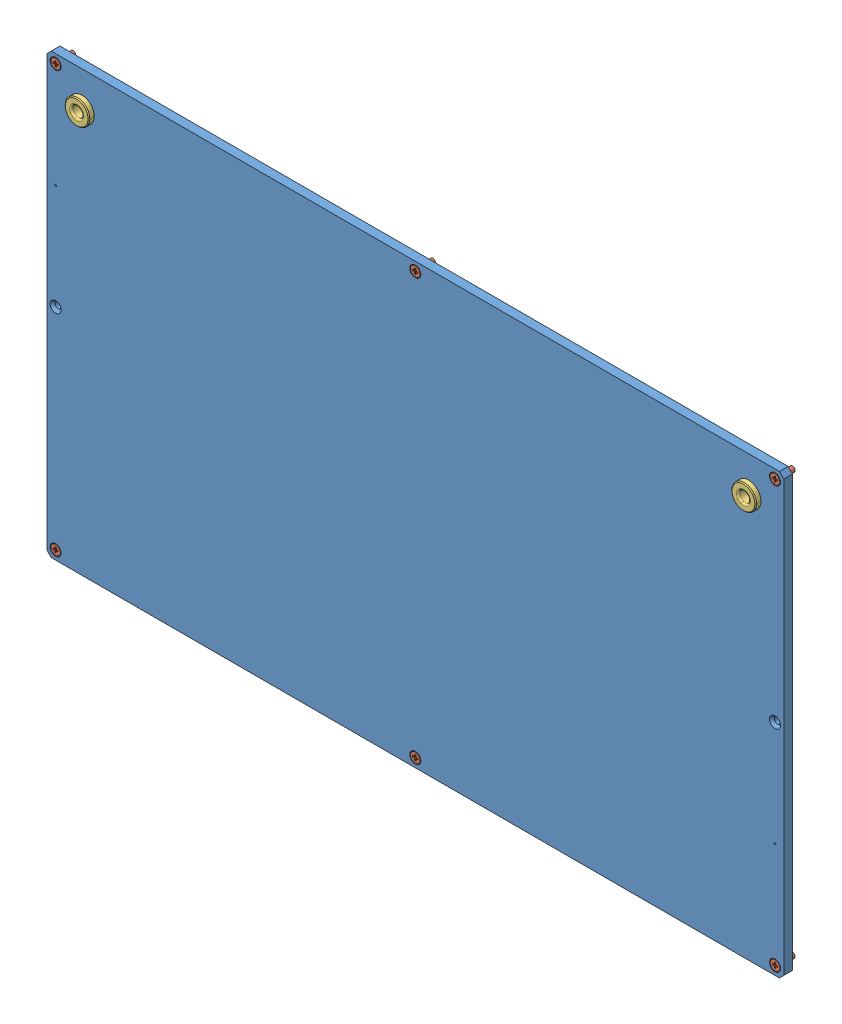
SolidWorks assembly NeedleBed, configuration Default. Lengths in mm.
Overall size (420 250 13).
9 component instances, 3 part files, 10 mates.
Components (placement in the parent):
- Needlebed-1: Needlebed [Default] at origin size (420 250 10)
- countersunk flat head cross recess screw_iso-4: countersunk flat head cross recess screw_iso [ISO 7046-1 - M3 x 10 - Z - 10N] at (-15 -15 0) x (0 0 -1) z (0.999972 -0.007459 0) size (10 5.5 5.5)
- countersunk flat head cross recess screw_iso-5: countersunk flat head cross recess screw_iso [ISO 7046-1 - M3 x 10 - Z - 10N] at (190 -15 0) x (0 0 -1) z (0.999968 -0.007971 0) size (10 5.5 5.5)
- countersunk flat head cross recess screw_iso-6: countersunk flat head cross recess screw_iso [ISO 7046-1 - M3 x 10 - Z - 10N] at (395 -15 0) x (0 0 -1) z (0.99999 -0.004523 0) size (10 5.5 5.5)
- countersunk flat head cross recess screw_iso-7: countersunk flat head cross recess screw_iso [ISO 7046-1 - M3 x 10 - Z - 10N] at (395 225 0) x (0 0 -1) z (0.99999 -0.004422 0) size (10 5.5 5.5)
- countersunk flat head cross recess screw_iso-8: countersunk flat head cross recess screw_iso [ISO 7046-1 - M3 x 10 - Z - 10N] at (190 225 0) x (0 0 -1) z (0.999918 -0.012792 0) size (10 5.5 5.5)
- countersunk flat head cross recess screw_iso-9: countersunk flat head cross recess screw_iso [ISO 7046-1 - M3 x 10 - Z - 10N] at (-15 225 0) x (0 0 -1) z (0.997473 0.071048 0) size (10 5.5 5.5)
- JBH6_10-1: JBH6_10 [Default] at (0 210 3) x (0 0 -1) z (1 0 0) size (13 14 14)
- JBH6_10-2: JBH6_10 [Default] at (380 210 3) x (0 0 -1) z (1 0 0) size (13 14 14)
Mates (geometry in assembly coordinates):
- Coincident1: coincident aligned: cone of Needlebed-1 through (-15 -15 0) axis (0 0 -1); cone of countersunk flat head cross recess screw_iso-4 through (-15 -15 -0.4) axis (0 0 -1)
- Coincident2: coincident aligned: cone of Needlebed-1 through (190 -15 0) axis (0 0 -1); cone of countersunk flat head cross recess screw_iso-5 through (190 -15 -0.4) axis (0 0 -1)
- Coincident3: coincident aligned: cone of Needlebed-1 through (395 -15 0) axis (0 0 -1); cone of countersunk flat head cross recess screw_iso-6 through (395 -15 -0.4) axis (0 0 -1)
- Coincident4: coincident aligned: cone of Needlebed-1 through (395 225 0) axis (0 0 -1); cone of countersunk flat head cross recess screw_iso-7 through (395 225 -0.4) axis (0 0 -1)
- Coincident5: coincident aligned: cone of Needlebed-1 through (190 225 0) axis (0 0 -1); cone of countersunk flat head cross recess screw_iso-8 through (190 225 -0.4) axis (0 0 -1)
- Coincident6: coincident aligned: cone of Needlebed-1 through (-15 225 0) axis (0 0 -1); cone of countersunk flat head cross recess screw_iso-9 through (-15 225 -0.4) axis (0 0 -1)
- Concentric3: concentric anti-aligned: cylinder of Needlebed-1 through (0 210 0) axis (0 0 1) radius 5; cylinder of JBH6_10-1 through (0 210 -10) axis (0 0 -1) radius 5
- Coincident9: coincident anti-aligned: plane of Needlebed-1 through (0 0 0) normal (0 0 1); plane of JBH6_10-1 through (0 217 0) normal (0 0 -1)
- Concentric4: concentric anti-aligned: cylinder of Needlebed-1 through (380 210 0) axis (0 0 1) radius 5; cylinder of JBH6_10-2 through (380 210 -10) axis (0 0 -1) radius 5
- Coincident10: coincident anti-aligned: plane of Needlebed-1 through (0 0 0) normal (0 0 1); plane of JBH6_10-2 through (380 217 0) normal (0 0 -1)
